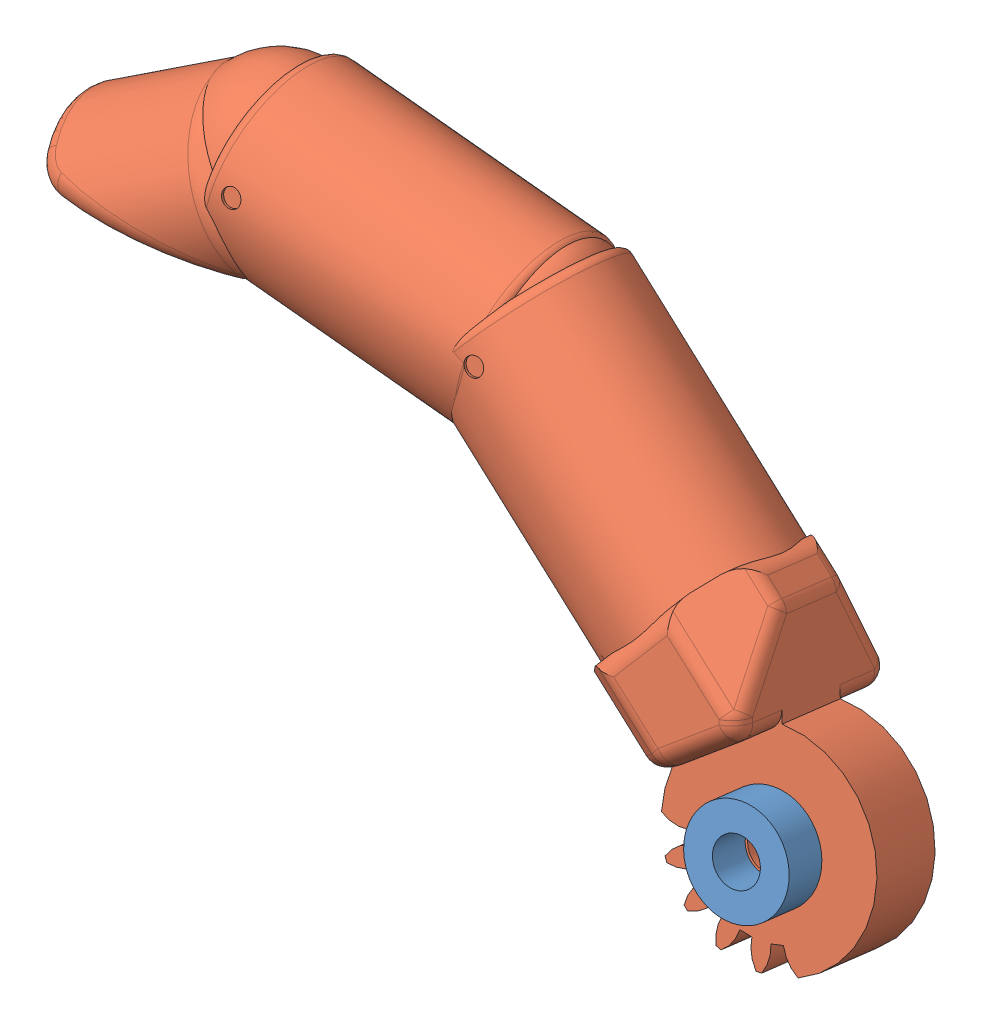
SolidWorks assembly figer1, configuration ﾃﾞﾌｫﾙﾄ. Lengths in mm.
Overall size (98.38 76.04 46.32).
3 component instances, 3 part files, 4 mates.
Components (placement in the parent):
- thrustBearing^BMIHand-1: thrustBearing^BMIHand [ﾃﾞﾌｫﾙﾄ] at (-86.2052 33.1376 117.7907) x (0.968907 0.190479 -0.157912) z (-0.114962 -0.218571 -0.969026) size (11 11 4.5) (virtual)
- cm3-1: cm3 [ﾃﾞﾌｫﾙﾄ] at (-66.8811 107.1827 78.6734) x (-0.985754 -0.095459 0.138478) z (-0.114962 -0.218571 -0.969026) size (89.25 64.71 21.39)
- F604ZZ-1: F604ZZ [ﾃﾞﾌｫﾙﾄ] at (-121.3498 62.6526 102.4033) x (0.976509 -0.203831 -0.069874) z (0.114962 0.218571 0.969026) size (13.5 13.5 4)
Mates (geometry in assembly coordinates):
- 同心円69: concentric aligned: circle of thrustBearing^BMIHand-1; circle of cm3-1
- 一致61: coincident anti-aligned: plane of cm3-1 through (-120.8899 63.5269 106.2794) normal (-0.114962 -0.218571 -0.969026); plane of F604ZZ-1 through (-120.8899 63.5269 106.2794) normal (0.114962 0.218571 0.969026)
- 同心円72: concentric aligned: circle of cm3-1; circle of F604ZZ-1
- Coincident5: coincident anti-aligned: plane of thrustBearing^BMIHand-1 through (-120.4301 64.4012 110.1555) normal (-0.114962 -0.218571 -0.969026); plane of cm3-1 through (-120.4301 64.4012 110.1555) normal (0.114962 0.218571 0.969026)
